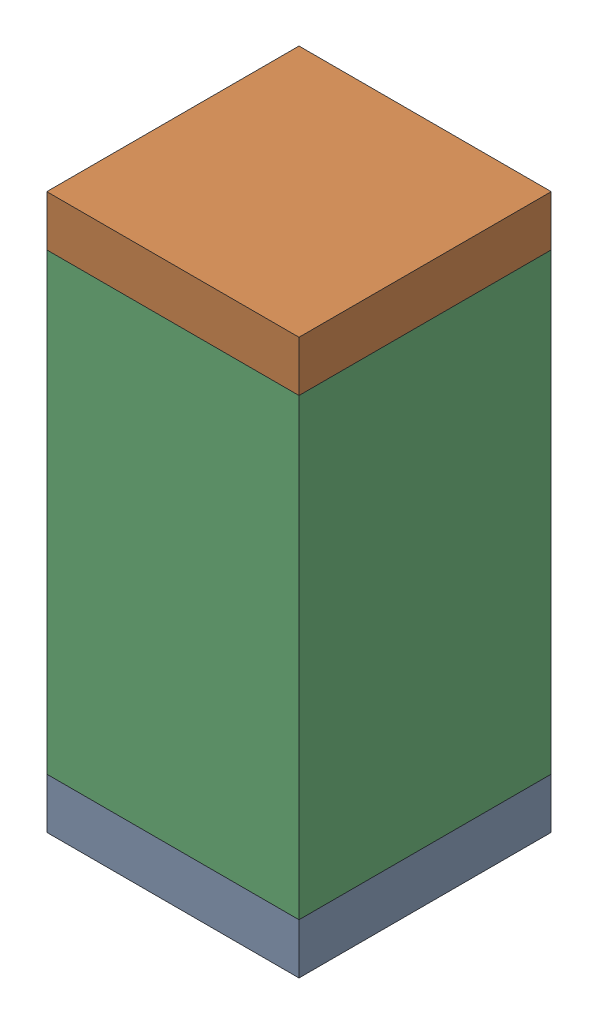
SolidWorks assembly C14, configuration Default. Lengths in mm.
Overall size (0.5 1.1 0.5).
6 component instances, 2 part files, 0 mates.
Components (placement in the parent):
- 810157360-1: 810157360 [Default] at (134.5 11.7 0) size (0.5 0.1 0.5)
  - Extruded_9-1: Extruded_9 [Default] at origin size (0.5 0.1 0.5)
- 810157360-2: 810157360 [Default] at (134.5 12.7 0) size (0.5 0.1 0.5)
  - Extruded_9-1: Extruded_9 [Default] at origin size (0.5 0.1 0.5)
- 791586336-1: 791586336 [Default] at (134.5 12.2 0) size (0.5 0.9 0.5)
  - Extruded_8-1: Extruded_8 [Default] at origin size (0.5 0.9 0.5)
